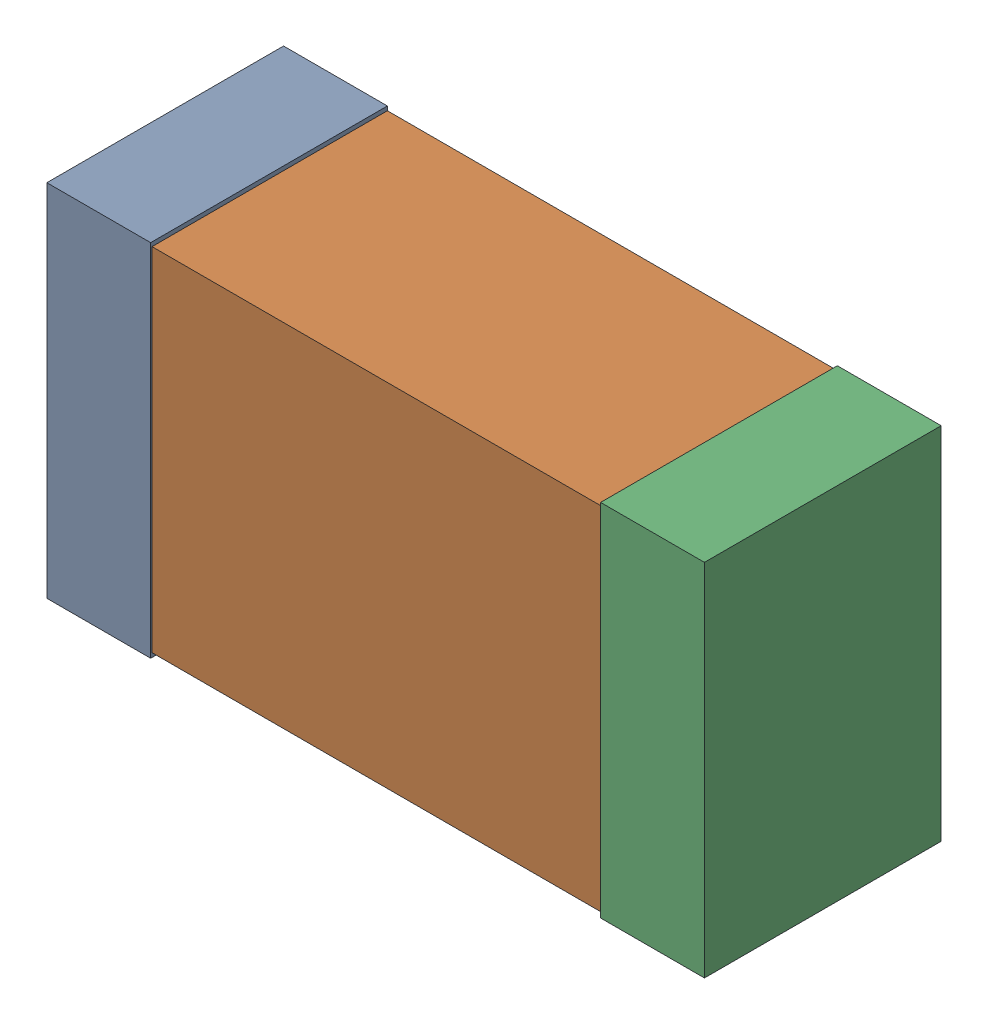
SolidWorks assembly R3_Motor_9Kanaloa_v2.0.0_Motor, configuration Default. Lengths in mm.
Overall size (2.38 1.3 0.85).
6 component instances, 2 part files, 0 mates.
Components (placement in the parent):
- 352877648-1: 352877648 [Default] at (41.613 175.768 0) size (0.38 1.3 0.85)
  - Extruded_14-1: Extruded_14 [Default] at origin size (0.38 1.3 0.85)
- 352877392-1: 352877392 [Default] at (42.613 175.768 0) size (2.2 1.27 0.85)
  - Extruded_15-1: Extruded_15 [Default] at origin size (2.2 1.27 0.85)
- 352877648-2: 352877648 [Default] at (43.613 175.768 0) size (0.38 1.3 0.85)
  - Extruded_14-1: Extruded_14 [Default] at origin size (0.38 1.3 0.85)
